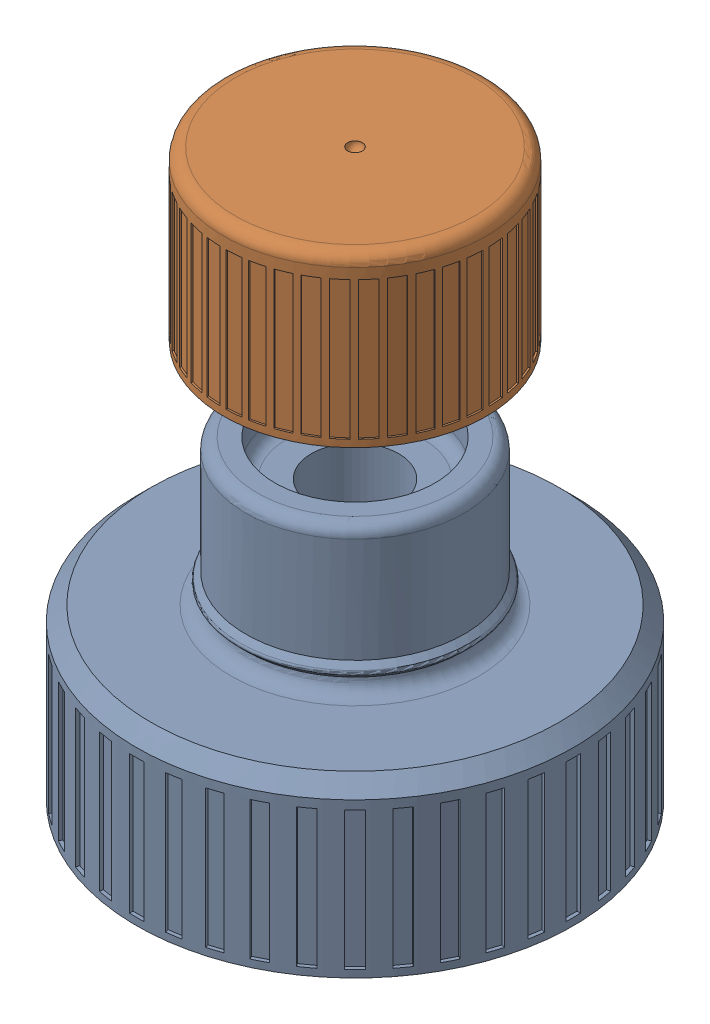
SolidWorks assembly bottle cap and snap-fit lid assembly, configuration Default. Lengths in mm.
2 component instances, 2 part files, 1 mates.
Components (placement in the parent):
- bottle cap-1: bottle cap [Default] at (7.4805 6.7442 31.0437) size (30 21.6 30)
- snap-fit lid-1: snap-fit lid [Default] at (7.4805 34.0798 31.0437) x (0.922515 0 0.385961) z (-0.385961 0 0.922515) size (18.06 11.52 18.06)
Mates (geometry in assembly coordinates):
- Concentric1: concentric aligned: cylinder of Protoypebottlecap-1-1 through (7.4805 28.3442 31.0437) axis (0 -1 0) radius 7.5; cylinder of snapfit-cap-1 through (7.4805 34.0798 31.0437) axis (0 -1 0) radius 7.53
